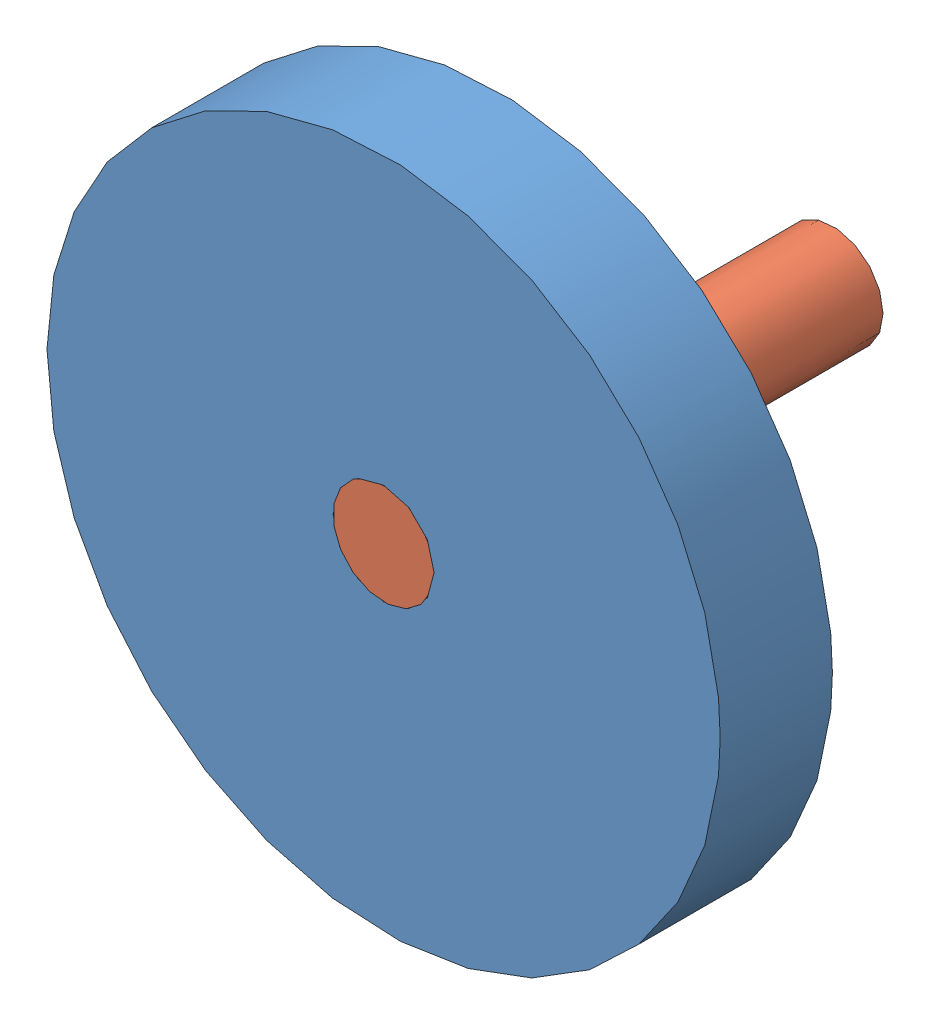
SolidWorks assembly Spur Gear and Shaft Assembly 5-3, configuration Default. Lengths in mm.
Overall size (120 120 80).
2 component instances, 2 part files, 2 mates.
Components (placement in the parent):
- Spur Gear 5-3-1: Spur Gear 5-3 [Default] at origin size (120 120 20)
- Spur Gear Shaft 5-3-1: Spur Gear Shaft 5-3 [Default] at (0 0 20) size (18.04 18.04 80)
Mates (geometry in assembly coordinates):
- Coincident1: coincident aligned: plane of Spur Gear 5-3-1 through (0 0 20) normal (0 0 1); plane of Spur Gear Shaft 5-3-1 through (0 0 20) normal (0 0 1)
- Concentric1: concentric anti-aligned: cylinder of Spur Gear 5-3-1 through (0 0 20) axis (0 0 -1) radius 9; cylinder of Spur Gear Shaft 5-3-1 through (0 0 -60) axis (0 0 1) radius 9.0195
